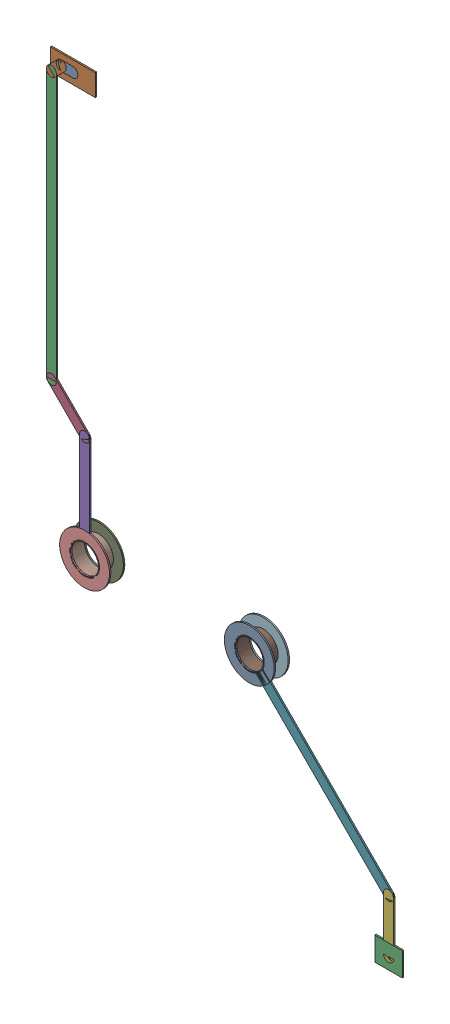
SolidWorks assembly NetIC2_7, configuration Predeterminado. Lengths in mm.
Overall size (9.07 16.07 0.39).
41 component instances, 11 part files, 0 mates.
Components (placement in the parent):
- Track (18.605mm,57mm)(18.902mm,57mm) on Top Layer-1: Track (18.605mm,57mm)(18.902mm,57mm) on Top Layer [Predeterminado] at origin size (0.55 0.25 0.04)
  - Track (18.605mm,57mm)(18.902mm,57mm) on Top Layer-1-1: Track (18.605mm,57mm)(18.902mm,57mm) on Top Layer-1 [Predeterminado] at (-68.317 -44.187 -0.0457) size (0.55 0.25 0.04)
    - Track (18.605mm,57mm)(18.902mm,57mm) on Top Layer-Part-1-1: Track (18.605mm,57mm)(18.902mm,57mm) on Top Layer-Part-1 [Predeterminado] at origin size (0.55 0.25 0.04)
- Track (18.353mm,56.749mm)(18.605mm,57mm) on Top Layer-1: Track (18.353mm,56.749mm)(18.605mm,57mm) on Top Layer [Predeterminado] at origin size (0.51 0.51 0.04)
  - Track (18.353mm,56.749mm)(18.605mm,57mm) on Top Layer-1-1: Track (18.353mm,56.749mm)(18.605mm,57mm) on Top Layer-1 [Predeterminado] at (-68.317 -44.187 -0.0457) size (0.51 0.51 0.04)
    - Track (18.353mm,56.749mm)(18.605mm,57mm) on Top Layer-Part-1-1: Track (18.353mm,56.749mm)(18.605mm,57mm) on Top Layer-Part-1 [Predeterminado] at origin size (0.51 0.51 0.04)
- Track (18.353mm,49.947mm)(18.353mm,56.749mm) on Top Layer-1: Track (18.353mm,49.947mm)(18.353mm,56.749mm) on Top Layer [Predeterminado] at origin size (0.25 7.06 0.04)
  - Track (18.353mm,49.947mm)(18.353mm,56.749mm) on Top Layer-1-1: Track (18.353mm,49.947mm)(18.353mm,56.749mm) on Top Layer-1 [Predeterminado] at (-68.317 -44.187 -0.0457) size (0.25 7.06 0.04)
    - Track (18.353mm,49.947mm)(18.353mm,56.749mm) on Top Layer-Part-1-1: Track (18.353mm,49.947mm)(18.353mm,56.749mm) on Top Layer-Part-1 [Predeterminado] at origin size (0.25 7.06 0.04)
- Track (18.353mm,49.947mm)(19.2mm,49.1mm) on Top Layer-1: Track (18.353mm,49.947mm)(19.2mm,49.1mm) on Top Layer [Predeterminado] at origin size (1.1 1.1 0.04)
  - Track (18.353mm,49.947mm)(19.2mm,49.1mm) on Top Layer-1-1: Track (18.353mm,49.947mm)(19.2mm,49.1mm) on Top Layer-1 [Predeterminado] at (-68.317 -44.187 -0.0457) size (1.1 1.1 0.04)
    - Track (18.353mm,49.947mm)(19.2mm,49.1mm) on Top Layer-Part-1-1: Track (18.353mm,49.947mm)(19.2mm,49.1mm) on Top Layer-Part-1 [Predeterminado] at origin size (1.1 1.1 0.04)
- Track (19.2mm,46.4mm)(19.2mm,49.1mm) on Top Layer-1: Track (19.2mm,46.4mm)(19.2mm,49.1mm) on Top Layer [Predeterminado] at origin size (0.25 2.49 0.04)
  - Track (19.2mm,46.4mm)(19.2mm,49.1mm) on Top Layer-1-1: Track (19.2mm,46.4mm)(19.2mm,49.1mm) on Top Layer-1 [Predeterminado] at (-68.317 -44.187 -0.0457) size (0.25 2.49 0.04)
    - Track (19.2mm,46.4mm)(19.2mm,49.1mm) on Top Layer-Part-1-1: Track (19.2mm,46.4mm)(19.2mm,49.1mm) on Top Layer-Part-1 [Predeterminado] at origin size (0.25 2.49 0.04)
- Track (26.95mm,41.5mm)(26.95mm,42.85mm) on Top Layer-1: Track (26.95mm,41.5mm)(26.95mm,42.85mm) on Top Layer [Predeterminado] at origin size (0.25 1.6 0.04)
  - Track (26.95mm,41.5mm)(26.95mm,42.85mm) on Top Layer-1-1: Track (26.95mm,41.5mm)(26.95mm,42.85mm) on Top Layer-1 [Predeterminado] at (-68.317 -44.187 -0.0457) size (0.25 1.6 0.04)
    - Track (26.95mm,41.5mm)(26.95mm,42.85mm) on Top Layer-Part-1-1: Track (26.95mm,41.5mm)(26.95mm,42.85mm) on Top Layer-Part-1 [Predeterminado] at origin size (0.25 1.6 0.04)
- Track (23.4mm,46.4mm)(26.95mm,42.85mm) on Top Layer-1: Track (23.4mm,46.4mm)(26.95mm,42.85mm) on Top Layer [Predeterminado] at origin size (3.53 3.53 0.04)
  - Track (23.4mm,46.4mm)(26.95mm,42.85mm) on Top Layer-1-1: Track (23.4mm,46.4mm)(26.95mm,42.85mm) on Top Layer-1 [Predeterminado] at (-68.317 -44.187 -0.0457) size (3.53 3.53 0.04)
    - Track (23.4mm,46.4mm)(26.95mm,42.85mm) on Top Layer-Part-1-1: Track (23.4mm,46.4mm)(26.95mm,42.85mm) on Top Layer-Part-1 [Predeterminado] at origin size (3.53 3.53 0.04)
- Via (19.2mm,46.4mm) from Top Layer to Bottom Layer-1: Via (19.2mm,46.4mm) from Top Layer to Bottom Layer [Predeterminado] at origin size (1.27 1.27 0.39)
  - Via Hole-1: Via Hole [Predeterminado] at (19.2 46.4 -0.4013) size (0.76 0.76 0.39)
    - Via Hole-Part-1-1: Via Hole-Part-1 [Predeterminado] at origin size (0.76 0.76 0.39)
  - Via Top Layer-1: Via Top Layer [Predeterminado] at (19.2 46.4 -0.4013) size (1.27 1.27 0.04)
    - Via Top Layer-Part-1-1: Via Top Layer-Part-1 [Predeterminado] at origin size (1.27 1.27 0.04)
  - Via Top Layer-2: Via Top Layer [Predeterminado] at (19.2 46.4 -0.0457) size (1.27 1.27 0.04)
    - Via Top Layer-Part-1-1: Via Top Layer-Part-1 [Predeterminado] at origin size (1.27 1.27 0.04)
- Via (23.4mm,46.4mm) from Top Layer to Bottom Layer-1: Via (23.4mm,46.4mm) from Top Layer to Bottom Layer [Predeterminado] at origin size (1.27 1.27 0.39)
  - Via Hole-1: Via Hole [Predeterminado] at (23.4 46.4 -0.4013) size (0.76 0.76 0.39)
    - Via Hole-Part-1-1: Via Hole-Part-1 [Predeterminado] at origin size (0.76 0.76 0.39)
  - Via Top Layer-1: Via Top Layer [Predeterminado] at (23.4 46.4 -0.4013) size (1.27 1.27 0.04)
    - Via Top Layer-Part-1-1: Via Top Layer-Part-1 [Predeterminado] at origin size (1.27 1.27 0.04)
  - Via Top Layer-2: Via Top Layer [Predeterminado] at (23.4 46.4 -0.0457) size (1.27 1.27 0.04)
    - Via Top Layer-Part-1-1: Via Top Layer-Part-1 [Predeterminado] at origin size (1.27 1.27 0.04)
- Pad ADXL345-7(18.902mm,57mm) on Top Layer-1: Pad ADXL345-7(18.902mm,57mm) on Top Layer [Predeterminado] at origin size (1.14 0.55 0.04)
  - Pad ADXL345-7(18.902mm,57mm) on Top Layer-1-1: Pad ADXL345-7(18.902mm,57mm) on Top Layer-1 [Predeterminado] at (-68.317 -44.187 -0.0457) size (1.14 0.55 0.04)
    - Pad ADXL345-7(18.902mm,57mm) on Top Layer-Part-1-1: Pad ADXL345-7(18.902mm,57mm) on Top Layer-Part-1 [Predeterminado] at origin size (1.14 0.55 0.04)
- Pad R4-2(26.95mm,41.5mm) on Top Layer-1: Pad R4-2(26.95mm,41.5mm) on Top Layer [Predeterminado] at origin size (0.7 0.6 0.04)
  - Pad R4-2(26.95mm,41.5mm) on Top Layer-1-1: Pad R4-2(26.95mm,41.5mm) on Top Layer-1 [Predeterminado] at (-68.317 -44.187 -0.0457) size (0.7 0.6 0.04)
    - Pad R4-2(26.95mm,41.5mm) on Top Layer-Part-1-1: Pad R4-2(26.95mm,41.5mm) on Top Layer-Part-1 [Predeterminado] at origin size (0.7 0.6 0.04)
